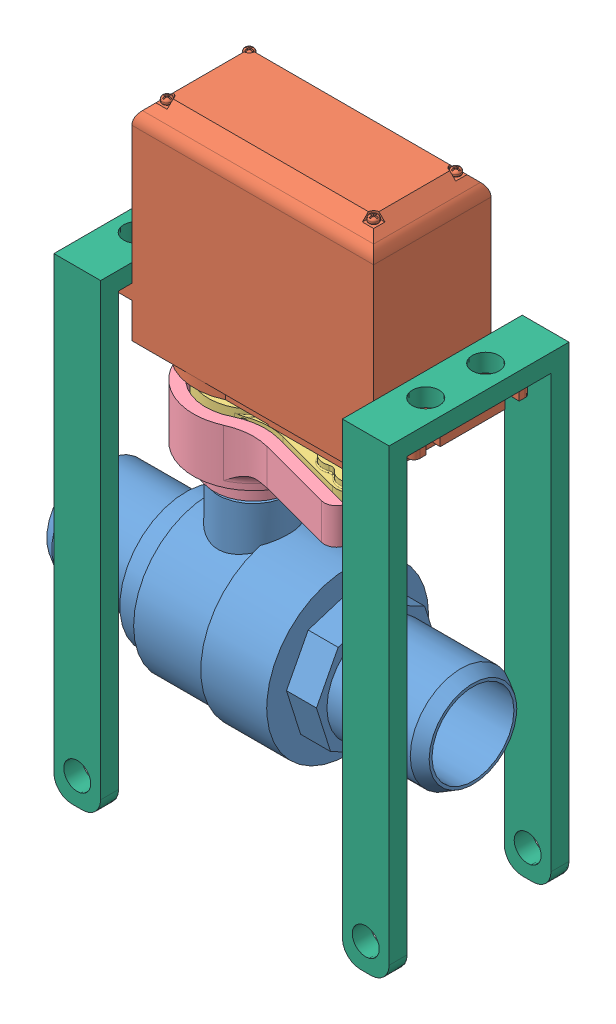
SolidWorks assembly ServoValve_Assembly, configuration Default. Lengths in mm.
Overall size (64.8 102.1 31.72).
7 component instances, 6 part files, 16 mates.
Components (placement in the parent):
- brass_ball_valve_dn20_barbed-1: brass_ball_valve_dn20_barbed [Default] at origin size (63.78 40.6 27)
- Standard Servo-1: Standard Servo [Default] at (6.4547 73.5 1.5943) x (-1 0 0) z (0 0 1) size (53.74 42.63 19.57)
- Servo_arm_25T-1: Servo_arm_25T [Default] at (-4.715 29.4 0) x (-0.966561 0 -0.256437) z (0.256437 0 -0.966561) size (33.87 4.68 15)
- servo_arm_valve_interface-1: servo_arm_valve_interface [Default] at (-4.715 19.9 0) x (0.966561 0 0.256437) z (-0.256437 0 0.966561) size (37.5 13 20)
- Nut-1: Nut [Default] at (-4.715 26.925 0) x (-0.771301 0 0.63647) z (-0.63647 0 -0.771301) size (10 4.05 11.25)
- Servo_pipe_interface-1: Servo_pipe_interface [Default] at (29.0114 49.5987 0) x (0 0 -1) z (1 0 0) size (30 78 7.8)
- Servo_pipe_interface-2: Servo_pipe_interface [Default] at (-19.1086 49.43 0) x (0 0 -1) z (1 0 0) size (30 78 7.8)
Mates (geometry in assembly coordinates):
- Concentric1: concentric anti-aligned: circle of brass_ball_valve_dn20_barbed-1; circle of Standard Servo-1
- Parallel1: parallel aligned: plane of brass_ball_valve_dn20_barbed-1 through (0 0 0) normal (0 0 1); plane of Standard Servo-1 through (6.4547 73.5 1.5943) normal (0 0 1)
- Coincident2: coincident anti-aligned: plane of Standard Servo-1 through (-4.715 30.9 0) normal (0 -1 0); plane of Servo_arm_25T-1 through (-4.715 30.9 0) normal (0 1 0)
- Concentric2: concentric aligned: cylinder of Standard Servo-1 through (-4.715 37.9 0) axis (0 -1 0) radius 1.27; cylinder of Servo_arm_25T-1 through (-4.715 29.4 0) axis (0 -1 0) radius 1.25
- Concentric3: concentric aligned: circle of brass_ball_valve_dn20_barbed-1; circle of servo_arm_valve_interface-1
- Coincident3: coincident anti-aligned: plane of brass_ball_valve_dn20_barbed-1 through (0 19.9 0) normal (0 1 0); plane of servo_arm_valve_interface-1 through (-4.715 19.9 0) normal (0 -1 0)
- Coincident4: coincident anti-aligned: plane of Servo_arm_25T-1 through (17.9992 29.4 6.0263) normal (0 -1 0); plane of servo_arm_valve_interface-1 through (-4.715 29.4 0) normal (0 1 0)
- Coincident5: coincident anti-aligned: plane of Servo_arm_25T-1 through (-4.715 29.4 0) normal (0.256437 0 -0.966561); plane of servo_arm_valve_interface-1 through (-4.715 19.9 0) normal (-0.256437 0 0.966561)
- Concentric4: concentric anti-aligned: cylinder of brass_ball_valve_dn20_barbed-1 through (-4.715 27.1 0) axis (0 -1 0) radius 2.625; cylinder of Nut-1 through (-4.715 24.899 0) axis (0 1 0) radius 2.6
- Coincident6: coincident anti-aligned: circle of servo_arm_valve_interface-1; plane of Nut-1 through (-4.715 24.9 0) normal (0 -1 0)
- Coincident8: coincident anti-aligned: plane of Standard Servo-1 through (31.8214 46.5987 9.785) normal (0 1 0); plane of Servo_pipe_interface-1 through (29.0114 46.5987 1.5867) normal (0 -1 0)
- Coincident11: coincident anti-aligned: plane of Standard Servo-1 through (-21.9186 46.43 -9.785) normal (0 1 0); plane of Servo_pipe_interface-2 through (-19.1086 46.43 0) normal (0 -1 0)
- Coincident12: coincident anti-aligned: plane of Standard Servo-1 through (-15.2086 38.13 -9.785) normal (-1 0 0); plane of Servo_pipe_interface-2 through (-15.2086 46.43 15) normal (1 0 0)
- Coincident13: coincident anti-aligned: plane of Standard Servo-1 through (25.1114 38.13 -9.785) normal (1 0 0); plane of Servo_pipe_interface-1 through (25.1114 46.5987 16.5867) normal (-1 0 0)
- Coincident14: coincident anti-aligned: plane of Servo_pipe_interface-2 through (-19.1086 49.43 0) normal (0 0 -1)
- Coincident15: coincident anti-aligned: plane of Servo_pipe_interface-1 through (29.0114 49.5987 0) normal (0 0 -1)
